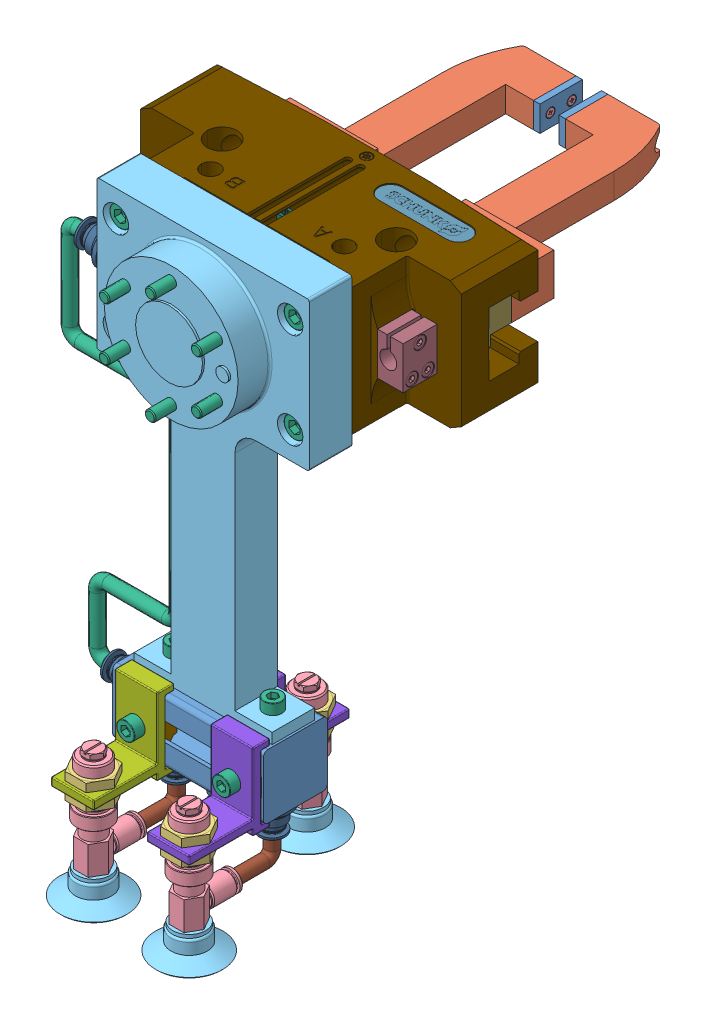
SolidWorks assembly doppio_gripper_completo, configuration Default. Lengths in mm.
Overall size (151.09 265 227.75).
73 component instances, 24 part files, 36 mates.
Components (placement in the parent):
- assieme_ventose-1: assieme_ventose [Default] at (367.5 -170.0409 9.326) x (0 -1 0) z (-1 0 0) size (78 109.5 91.15)
  - aluminiumm 30x30 670mm-1: aluminiumm 30x30 670mm [Default] at (-0.0409 0.674 335) size (30 30 71)
  - ecrou profil-1: ecrou profil [Default] at (-0.0409 9.834 352.85) x (-1 0 0) z (0 -1 0) size (15.9 15.7 7.3)
  - 189174_ESG-30-SF-HD-QS.stp-1: 189174_ESG-30-SF-HD-QS.stp [Default] at (48.9591 39.674 390) x (0 -1 0) z (0 0 -1) size (36.15 61.01 31.5)
    - 130519 ESHM-M14x1.stp-1: 130519 ESHM-M14x1.stp [Default] at (0 38 0) size (19.64 4.01 19.64)
    - 130519 ESHM-M14x1.stp-2: 130519 ESHM-M14x1.stp [Default] at (0 30 0) size (19.64 4.01 19.64)
    - 189239 ESH-HD-4-QS_part---(0).stp-1: 189239 ESH-HD-4-QS_part---(0).stp [Default] at origin size (28.4 50.01 16)
    - 189302 ESS-30-SF.stp-1: 189302 ESS-30-SF.stp [Default] at (0 -11 0) size (31.5 16 31.5)
  - socket head cap screw_iso-3: socket head cap screw_iso [ISO 4762 M5 x 12 - 12N] at (-0.0409 24.674 345) x (0 -1 0) z (-0.866025 0 0.5) size (17 8.5 8.5)
  - socket head cap screw_iso-4: socket head cap screw_iso [ISO 4762 M5 x 12 - 12N] at (-0.0409 24.674 390) x (0 -1 0) z (-0.866025 0 -0.5) size (17 8.5 8.5)
  - 189174_ESG-30-SF-HD-QS.stp-2: 189174_ESG-30-SF-HD-QS.stp [Default] at (48.9591 -38.326 367.5) x (0 1 0) z (0 0 1) size (36.15 61.01 31.5)
    - 130519 ESHM-M14x1.stp-1: 130519 ESHM-M14x1.stp [Default] at (0 38 0) size (19.64 4.01 19.64)
    - 130519 ESHM-M14x1.stp-2: 130519 ESHM-M14x1.stp [Default] at (0 30 0) size (19.64 4.01 19.64)
    - 189239 ESH-HD-4-QS_part---(0).stp-1: 189239 ESH-HD-4-QS_part---(0).stp [Default] at origin size (28.4 50.01 16)
    - 189302 ESS-30-SF.stp-1: 189302 ESS-30-SF.stp [Default] at (0 -11 0) size (31.5 16 31.5)
  - Parte12-1: Parte12 [Default] at (14.9591 39.674 390) x (0 -1 0) z (-1 0 0) size (38 20 36)
  - 189174_ESG-30-SF-HD-QS.stp-4: 189174_ESG-30-SF-HD-QS.stp [Default] at (48.9591 39.674 345) x (0 -1 0) z (0 0 -1) size (36.15 61.01 31.5)
    - 130519 ESHM-M14x1.stp-1: 130519 ESHM-M14x1.stp [Default] at (0 38 0) size (19.64 4.01 19.64)
    - 130519 ESHM-M14x1.stp-2: 130519 ESHM-M14x1.stp [Default] at (0 30 0) size (19.64 4.01 19.64)
    - 189239 ESH-HD-4-QS_part---(0).stp-1: 189239 ESH-HD-4-QS_part---(0).stp [Default] at origin size (28.4 50.01 16)
    - 189302 ESS-30-SF.stp-1: 189302 ESS-30-SF.stp [Default] at (0 -11 0) size (31.5 16 31.5)
  - Parte12_-1: Parte12_ [Default] at (14.9591 39.674 345) x (0 -1 0) z (-1 0 0) size (38 20 36)
  - Parte12_-2: Parte12_ [Default] at (14.9591 -38.326 367.5) x (0 1 0) z (-1 0 0) size (38 20 36)
  - ecrou profil_-1: ecrou profil_ [Default] at (-0.0409 9.834 382.15) x (1 0 0) z (0 -1 0) size (15.9 15.7 7.3)
  - ecrou profil_-2: ecrou profil_ [Default] at (-0.0409 -8.486 375.35) x (1 0 0) z (0 1 0) size (15.9 15.7 7.3)
  - socket head cap screw_iso-7: socket head cap screw_iso [ISO 4762 M5 x 12 - 12N] at (-0.0409 -23.326 367.5) x (0 1 0) z (0 0 -1) size (17 8.5 8.5)
  - 186108_QS-G1_4-6-I.stp-4: 186108_QS-G1_4-6-I.stp [Default] at (14.9591 0.6232 390) x (0 0 1) z (-1 0 0) size (17 17 20.2)
  - 186108_QS-G1_4-6-I.stp-5: 186108_QS-G1_4-6-I.stp [Default] at (14.9591 0.6232 367.5) x (0 0 1) z (-1 0 0) size (17 17 20.2)
  - 186108_QS-G1_4-6-I.stp-6: 186108_QS-G1_4-6-I.stp [Default] at (14.9591 0.6232 345) x (0 0 1) z (-1 0 0) size (17 17 20.2)
  - tubi_racc-1: tubi_racc [Default] at (14.9591 0.674 335) x (0 0 -1) z (1 0 0) size (51 64 28.5)
  - 186108_QS-G1_4-6-I.stp-7: 186108_QS-G1_4-6-I.stp [Default] at (-0.0409 0.674 405) x (-0.923728 -0.383049 0) z (0 0 -1) size (17 17 20.2)
- pinza_con_dita-1: pinza_con_dita [Default] at (-88.6356 -83.6124 -120.7912) size (151 60 163)
  - SCHUNK_1460275_JGP_P_125_1_000ohne-1: SCHUNK_1460275_JGP_P_125_1_000ohne [Default] at (88.6356 83.6124 120.7912) size (151 60 63)
    - SCHUNK_1460275_JGP_P_125_1_000ohne_3-1: SCHUNK_1460275_JGP_P_125_1_000ohne_3 [Default] at (-0.75 0 -39.1) x (0 1 0) z (-1 0 0) size (30 23.9 61.3)
    - SCHUNK_1460275_JGP_P_125_1_000ohne_3-2: SCHUNK_1460275_JGP_P_125_1_000ohne_3 [Default] at (0.75 0 -39.1) x (0 -1 0) z (1 0 0) size (30 23.9 61.3)
    - SCHUNK_1460275_JGP_P_125_1_000ohne_6-1: SCHUNK_1460275_JGP_P_125_1_000ohne_6 [Default] at (-53 0 -25.15) x (-1 0 0) z (0 1 0) size (12 16 20)
    - SCHUNK_1460275_JGP_P_125_1_000ohne_6-2: SCHUNK_1460275_JGP_P_125_1_000ohne_6 [Default] at (53 0 -9.15) x (1 0 0) z (0 1 0) size (12 16 20)
    - SCHUNK_1460275_JGP_P_125_1_000ohne_9-1: SCHUNK_1460275_JGP_P_125_1_000ohne_9 [Default] at (36.65 29.3 -47.65) x (1 0 0) z (0 1 0) size (43 11 0.3)
    - SCHUNK_1460275_JGP_P_125_1_000ohne_11-1: SCHUNK_1460275_JGP_P_125_1_000ohne_11 [Default] at (3 26.125 -16) size (3.8 2.96 5)
    - SCHUNK_1460275_JGP_P_125_1_000ohne_13-1: SCHUNK_1460275_JGP_P_125_1_000ohne_13 [Default] at (0 0 -5.5) x (-1 0 0) z (0 0 1) size (85.9 59.7 5.4)
    - SCHUNK_1460275_JGP_P_125_1_000ohne_15-1: SCHUNK_1460275_JGP_P_125_1_000ohne_15 [Default] at (0 0 -61) x (0 -1 0) z (0 0 -1) size (56.8 43.3 6.15)
    - SCHUNK_1460275_JGP_P_125_1_000ohne_17-1: SCHUNK_1460275_JGP_P_125_1_000ohne_17 [Default] x (1 0 0) z (0 1 0) size (151 62 60)
  - chela-1: chela [Default] at (169.8768 23.5753 87.8636) x (-1 0 0) z (0 0 -1) size (57.55 19.7 100.99)
    - gommino-1: gommino [Default] at (73.7442 50.1871 130.0724) x (0 0 -1) z (1 0 0) size (20 19.7 3)
    - chela_senza_gommino-1: chela_senza_gommino [Default] at (19.1912 50.1871 30.0724) size (54.55 19.7 100.99)
  - chela-3: chela [Default] at (7.3944 143.6495 87.8636) x (1 0 0) z (0 0 -1) size (57.55 19.7 100.99)
    - gommino-1: gommino [Default] at (73.7442 50.1871 130.0724) x (0 0 -1) z (1 0 0) size (20 19.7 3)
    - chela_senza_gommino-1: chela_senza_gommino [Default] at (19.1912 50.1871 30.0724) size (54.55 19.7 100.99)
  - socket countersunk head screw_iso-3: socket countersunk head screw_iso [ISO 10642 - M4 x 35 - 20N] at (143.1356 83.6124 37.0112) x (0 0 1) z (-0.999808 0.019592 0) size (35 7.53 7.53)
  - socket countersunk head screw_iso-5: socket countersunk head screw_iso [ISO 10642 - M4 x 35 - 20N] at (119.0725 83.6124 37.0112) x (0 0 1) z (-1 0 0) size (35 7.53 7.53)
  - countersunk flat head cross recess screw_iso-1: countersunk flat head cross recess screw_iso [ISO 7046-1 - M2 x 8 - Z - 8N] at (93.1325 83.6124 -27.2088) x (1 0 0) z (0 -0.924225 -0.381849) size (8 3.8 3.8)
  - countersunk flat head cross recess screw_iso-2: countersunk flat head cross recess screw_iso [ISO 7046-1 - M2 x 8 - Z - 8N] at (93.1325 83.6124 -37.2088) size (8 3.8 3.8)
  - socket countersunk head screw_iso-7: socket countersunk head screw_iso [ISO 10642 - M4 x 35 - 20N] at (34.1356 83.6124 37.0112) x (0 0 1) z (-0.999808 -0.019592 0) size (35 7.53 7.53)
  - countersunk flat head cross recess screw_iso-3: countersunk flat head cross recess screw_iso [ISO 7046-1 - M2 x 8 - Z - 8N] at (84.1387 83.6124 -27.2088) x (-1 0 0) z (0 0.924225 0.381849) size (8 3.8 3.8)
  - countersunk flat head cross recess screw_iso-4: countersunk flat head cross recess screw_iso [ISO 7046-1 - M2 x 8 - Z - 8N] at (84.1387 83.6124 -37.2088) x (-1 0 0) z (0 0 -1) size (8 3.8 3.8)
  - socket countersunk head screw_iso-8: socket countersunk head screw_iso [ISO 10642 - M4 x 35 - 20N] at (58.1987 83.6124 37.0112) x (0 0 1) z (-1 0 0) size (35 7.53 7.53)
- flangia_2600-1: flangia_2600 [Default] at (-1460 0 35) x (-1 0 0) z (0 0 -1) size (100 199.14 36)
- socket head cap screw_iso-4: socket head cap screw_iso [ISO 4762 M5 x 35 - 22N] at (21.6506 12.5 5) x (0 0 1) z (0.5 -0.866025 0) size (40 8.5 8.5)
- socket head cap screw_iso-7: socket head cap screw_iso [ISO 4762 M5 x 35 - 22N] at (0 25 5) x (0 0 1) z (1 0 0) size (40 8.5 8.5)
- socket head cap screw_iso-8: socket head cap screw_iso [ISO 4762 M5 x 35 - 22N] at (-21.6506 12.5 5) x (0 0 1) z (0.5 0.866025 0) size (40 8.5 8.5)
- socket head cap screw_iso-9: socket head cap screw_iso [ISO 4762 M5 x 35 - 22N] at (-21.6506 -12.5 5) x (0 0 1) z (-0.5 0.866025 0) size (40 8.5 8.5)
- socket head cap screw_iso-10: socket head cap screw_iso [ISO 4762 M5 x 35 - 22N] at (0 -25 5) x (0 0 1) z (-1 0 0) size (40 8.5 8.5)
- socket head cap screw_iso-11: socket head cap screw_iso [ISO 4762 M5 x 35 - 22N] at (21.6506 -12.5 5) x (0 0 1) z (-0.5 -0.866025 0) size (40 8.5 8.5)
- socket head cap screw_iso-13: socket head cap screw_iso [ISO 4762 M6 x 25 - 25N] at (41 -22.5 18) x (0 0 -1) z (1 0 0) size (31 10 10)
- socket head cap screw_iso-14: socket head cap screw_iso [ISO 4762 M6 x 25 - 25N] at (41 22.5 18) x (0 0 -1) z (1 0 0) size (31 10 10)
- socket head cap screw_iso-15: socket head cap screw_iso [ISO 4762 M6 x 25 - 25N] at (-41 22.5 18) x (0 0 -1) z (1 0 0) size (31 10 10)
- socket head cap screw_iso-16: socket head cap screw_iso [ISO 4762 M6 x 25 - 25N] at (-41 -22.5 18) x (0 0 -1) z (1 0 0) size (31 10 10)
- ecrou profil_-1: ecrou profil_ [Default] at (30.7 -160.86 10) x (0 0 1) z (0 -1 0) size (15.9 15.7 7.3)
- ecrou profil_-2: ecrou profil_ [Default] at (-30.7 -160.86 10) x (0 0 -1) z (0 -1 0) size (15.9 15.7 7.3)
- socket head cap screw_iso-17: socket head cap screw_iso [ISO 4762 M5 x 12 - 12N] at (-22.85 -145 10) x (0 -1 0) z (0.5 0 0.866025) size (17 8.5 8.5)
- socket head cap screw_iso-18: socket head cap screw_iso [ISO 4762 M5 x 12 - 12N] at (22.85 -145 10) x (0 -1 0) z (-1 0 0) size (17 8.5 8.5)
- Parte1^doppio_gripper_completo-1: Parte1^doppio_gripper_completo [Default] at origin size (56.93 176 6) (virtual)
- 186108_QS-G1_4-6-I.stp-1: 186108_QS-G1_4-6-I.stp [Default] at (-50 0 10) x (0 0 -1) z (1 0 0) size (17 17 20.2)
Mates (geometry in assembly coordinates):
- Concentrico1: concentric aligned: cylinder of pinza_con_dita-1/SCHUNK_1460275_JGP_P_125_1_000ohne-1/SCHUNK_1460275_JGP_P_125_1_000ohne_17-1 through (-41 22.5 0) axis (0 0 1) radius 3.4; cylinder of flangia_2600-1 through (-41 22.5 0) axis (0 0 1) radius 3.4
- Coincidente16: coincident anti-aligned: plane of pinza_con_dita-1/SCHUNK_1460275_JGP_P_125_1_000ohne-1/SCHUNK_1460275_JGP_P_125_1_000ohne_17-1 through (0 0 0) normal (0 0 1); plane of flangia_2600-1 through (-1460 0 0) normal (0 0 -1)
- Coincidente17: coincident aligned: plane of pinza_con_dita-1/SCHUNK_1460275_JGP_P_125_1_000ohne-1/SCHUNK_1460275_JGP_P_125_1_000ohne_17-1 through (-50 30 0) normal (-1 0 0); plane of flangia_2600-1 through (-50 35 0) normal (-1 0 0)
- Coincidente18: coincident anti-aligned: plane of flangia_2600-1 through (21.6506 12.5 10) normal (0 0 -1); plane of socket head cap screw_iso-4 through (17.97 10.375 10) normal (0 0 1)
- Parallelo3: parallel aligned: plane of flangia_2600-1 through (50 35 0) normal (1 0 0); plane of socket head cap screw_iso-4 through (19.6086 11.3211 7.5) normal (1 0 0)
- Concentrico5: concentric aligned: cylinder of flangia_2600-1 through (41 -22.5 0) axis (0 0 1) radius 3.4; cylinder of socket head cap screw_iso-13 through (41 -22.5 49.75) axis (0 0 1) radius 5
- Coincidente20: coincident anti-aligned: plane of flangia_2600-1 through (41 -22.5 12) normal (0 0 1); plane of socket head cap screw_iso-13 through (41 -17.5 12) normal (0 0 -1)
- Concentrico6: concentric aligned: cylinder of flangia_2600-1 through (41 22.5 12) axis (0 0 1) radius 6; cylinder of socket head cap screw_iso-14 through (41 22.5 49.75) axis (0 0 1) radius 5
- Coincidente21: coincident anti-aligned: plane of flangia_2600-1 through (41 22.5 12) normal (0 0 1); plane of socket head cap screw_iso-14 through (41 27.5 12) normal (0 0 -1)
- Concentrico71: concentric aligned: cylinder of flangia_2600-1 through (-41 22.5 12) axis (0 0 1) radius 6; cylinder of socket head cap screw_iso-15 through (-41 22.5 49.75) axis (0 0 1) radius 5
- Coincidente221: coincident anti-aligned: plane of flangia_2600-1 through (-41 22.5 12) normal (0 0 1); plane of socket head cap screw_iso-15 through (-41 27.5 12) normal (0 0 -1)
- Concentrico8: concentric aligned: cylinder of flangia_2600-1 through (-41 -22.5 0) axis (0 0 1) radius 3.4; cylinder of socket head cap screw_iso-16 through (-41 -22.5 49.75) axis (0 0 1) radius 5
- Coincidente23: coincident anti-aligned: plane of flangia_2600-1 through (-41 -22.5 12) normal (0 0 1); plane of socket head cap screw_iso-16 through (-41 -17.5 12) normal (0 0 -1)
- Parallelo4: parallel anti-aligned: plane of flangia_2600-1 through (50 -35 0) normal (0 -1 0); plane of vassoioX1_componibile-1 through (302.4303 -434.8296 1005.4861) normal (0 1 0)
- Parallelo6: parallel aligned: plane of flangia_2600-1 through (-50 35 0) normal (-1 0 0); plane of assiene_distributore_valvola-1/7849_FR-4-1_4-C.stp-1/7849 FR-4-1_4-C - P1.stp-1 through (290.2496 -357.8805 979.0236) normal (0 0 -1)
- Parallelo7: parallel aligned: plane of flangia_2600-1 through (50 35 0) normal (0 1 0); plane of assiene_distributore_valvola-1/7849_FR-4-1_4-C.stp-1/7849 FR-4-1_4-C - P1.stp-1 through (290.2496 -268.8805 1009.0236) normal (0 1 0)
- Coincidente29: coordinate: unknown of pinza_con_dita-1/SCHUNK_1460275_JGP_P_125_1_000ohne-1
- Concentrico72: concentric aligned: cylinder of flangia_2600-1 through (21.6506 12.5 10) axis (0 0 -1) radius 5; cylinder of socket head cap screw_iso-4 through (21.6506 12.5 -26.75) axis (0 0 -1) radius 2.5
- Coincidente222: coincident anti-aligned: plane of assieme_ventose-1/aluminiumm 30x30 670mm-1 through (-32.5 -155 -5) normal (0 1 0); plane of flangia_2600-1 through (5.76 -155 143.6932) normal (0 -1 0)
- Coincidente223: coincident aligned: plane of assieme_ventose-1/aluminiumm 30x30 670mm-1 through (32.5 -170 10) normal (0 0 1); plane of flangia_2600-1 through (-1460 0 10) normal (0 0 1)
- Coincidente224: coincident anti-aligned: plane of assieme_ventose-1/189174_ESG-30-SF-HD-QS.stp-2/189239 ESH-HD-4-QS_part---(0).stp-1 through (0 -219 -29) normal (-1 0 0); plane of pinza_con_dita-1/SCHUNK_1460275_JGP_P_125_1_000ohne-1/SCHUNK_1460275_JGP_P_125_1_000ohne_17-1 through (0 0 0) normal (1 0 0)
- Coincidente225: coincident anti-aligned: plane of flangia_2600-1 through (15 -35 143.6932) normal (1 0 0); plane of ecrou profil_-1 through (15 -160.86 10) normal (-1 0 0)
- Coincidente226: coincident aligned: plane of flangia_2600-1 through (-33.9514 -156.76 14.3) normal (0 1 0); plane of ecrou profil_-1 through (15 -156.76 17.95) normal (0 1 0)
- Coincidente227: coincident aligned: plane of flangia_2600-1 through (-1460 0 10) normal (0 0 1); plane of ecrou profil_-1 through (30.7 -160.86 10) normal (0 0 1)
- Coincidente228: coincident aligned: plane of ecrou profil_-1 through (15 -155.06 6) normal (0 1 0); plane of ecrou profil_-2 through (-15 -155.06 14) normal (0 1 0)
- Coincidente229: coincident anti-aligned: plane of flangia_2600-1 through (-15 -35 143.6932) normal (-1 0 0); plane of ecrou profil_-2 through (-15 -160.86 10) normal (1 0 0)
- Coincidente230: coincident aligned: plane of ecrou profil_-1 through (15 -156.76 6) normal (0 0 -1); plane of ecrou profil_-2 through (-15 -156.76 6) normal (0 0 -1)
- Concentrico73: concentric anti-aligned: cylinder of flangia_2600-1 through (-22.85 35.001 10) axis (0 -1 0) radius 2.5; cylinder of socket head cap screw_iso-17 through (-22.85 -113.25 10) axis (0 1 0) radius 4.25
- Coincidente231: coincident anti-aligned: plane of flangia_2600-1 through (32.5 -150 0) normal (0 1 0); plane of socket head cap screw_iso-17 through (-19.1694 -150 7.875) normal (0 -1 0)
- Concentrico74: concentric anti-aligned: cylinder of flangia_2600-1 through (22.85 35.001 10) axis (0 -1 0) radius 2.5; cylinder of socket head cap screw_iso-18 through (22.85 -113.25 10) axis (0 1 0) radius 4.25
- Coincidente232: coincident anti-aligned: plane of flangia_2600-1 through (32.5 -150 0) normal (0 1 0); plane of socket head cap screw_iso-18 through (22.85 -150 14.25) normal (0 -1 0)
- Parallelo8: parallel aligned: plane of flangia_2600-1 through (15 -35 143.6932) normal (1 0 0); plane of socket head cap screw_iso-18 through (20.808 -147.5 8.8211) normal (1 0 0)
- Parallelo9: parallel aligned: plane of flangia_2600-1 through (-15 -35 143.6932) normal (-1 0 0); plane of socket head cap screw_iso-17 through (-20.808 -147.5 8.8211) normal (-1 0 0)
- Coincidente235: coincident anti-aligned: plane of flangia_2600-1 through (-50 35 0) normal (-1 0 0); plane of 186108_QS-G1_4-6-I.stp-1 through (-50 6.5785 10) normal (1 0 0)
- Coincidente236: coincident aligned: plane of pinza_con_dita-1/SCHUNK_1460275_JGP_P_125_1_000ohne-1/SCHUNK_1460275_JGP_P_125_1_000ohne_17-1 through (0 0 0) normal (0 1 0); plane of 186108_QS-G1_4-6-I.stp-1 through (-50 0 10) normal (0 1 0)
- Coincidente238: coincident anti-aligned: plane of flangia_2600-1 through (-1460 0 10) normal (0 0 1); plane of 186108_QS-G1_4-6-I.stp-1 through (-50 0 10) normal (0 0 -1)
